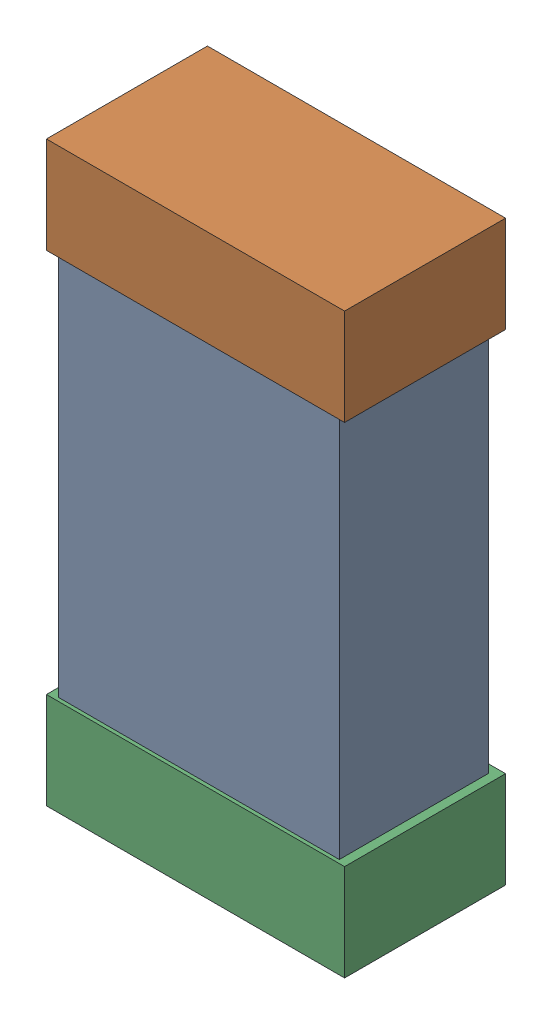
SolidWorks assembly C2, configuration Default. Lengths in mm.
Overall size (0.85 1.65 0.46).
6 component instances, 2 part files, 0 mates.
Components (placement in the parent):
- 432124816_30-1: 432124816_30 [Default] at (38.5458 19.0611 0.025) size (0.8 1.5 0.42)
  - Extruded (1)-1: Extruded (1) [Default] at origin size (0.8 1.5 0.42)
- 432138512_60-1: 432138512_60 [Default] at (38.5458 19.747 0.001) size (0.85 0.28 0.46)
  - Extruded-1: Extruded [Default] at origin size (0.85 0.28 0.46)
- 432138512_61-1: 432138512_61 [Default] at (38.5458 18.3754 0.001) size (0.85 0.28 0.46)
  - Extruded-1: Extruded [Default] at origin size (0.85 0.28 0.46)
